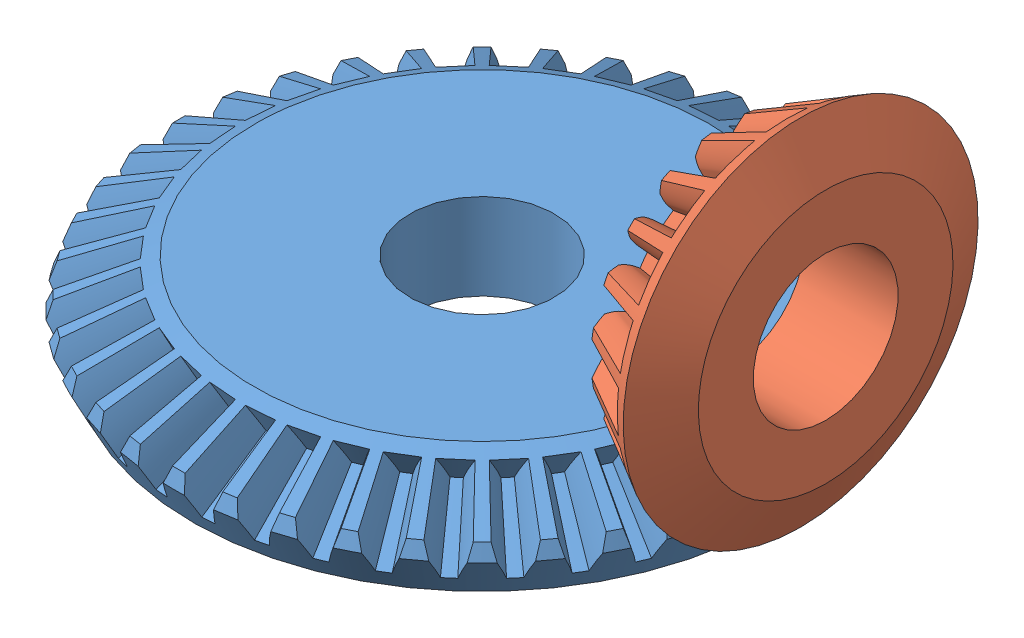
SolidWorks assembly Plain Bevel Test Assembly, configuration Default. Lengths in mm.
Overall size (65.4 78.2 55.4).
2 component instances, 2 part files, 3 mates.
Components (placement in the parent):
- Plain Inner Bevel Gear-1: Plain Inner Bevel Gear [Default] x (0.996926 0 0.078352) z (-0.078352 0 0.996926) size (57.28 63.5 51.06)
- Plain Outer Bevel Gear-2: Plain Outer Bevel Gear [Default] at origin size (31.75 78.2 29.4)
Mates (geometry in assembly coordinates):
- Coincident3: coordinate: point of new Outer Bevel Gear-1
- Coincident4: coincident aligned: line of Inner Bevel Gear-1 through (0 0 0) axis (0 -1 0); line of new Outer Bevel Gear-1 through (63.5 0 0) axis (0 0 -1)
- Coincident5: coincident: point of Plain Inner Bevel Gear-1; point of Plain Outer Bevel Gear-2
